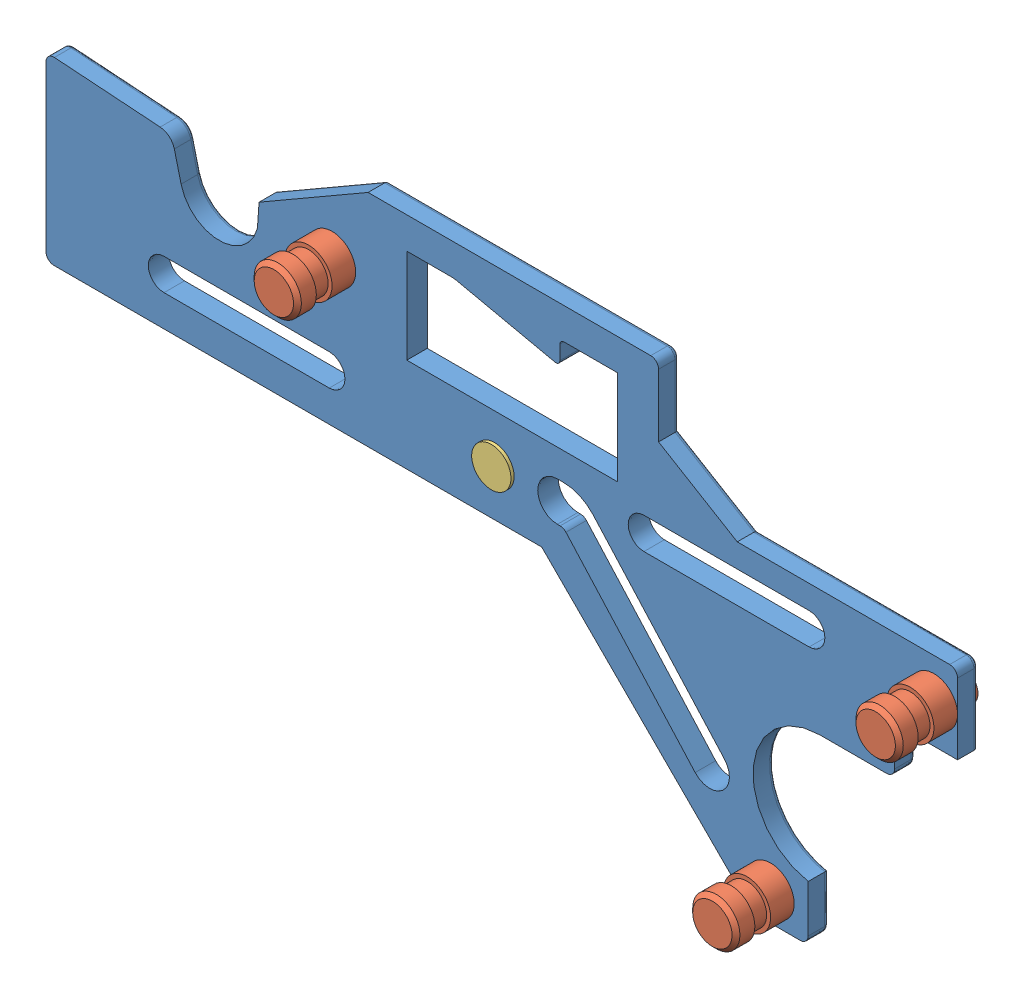
SolidWorks assembly plaque, configuration Défaut. Lengths in mm.
Overall size (115.86 55.31 11.5).
5 component instances, 3 part files, 8 mates.
Components (placement in the parent):
- Pièce8-1: Pièce8 [Défaut] at (-51.9489 -2.022 0) size (115.86 54.87 2.63)
- Pièce9-1: Pièce9 [Défaut] at (-15.5889 16.4069 10) x (0 0 -1) z (1 0 0) size (11 6 6)
- Pièce9-2: Pièce9 [Défaut] at (60.9111 5.978 10) x (0 0 -1) z (1 0 0) size (11 6 6)
- Pièce9-3: Pièce9 [Défaut] at (40.1491 -25.25 10) x (0 0 -1) z (0.486722 0.873557 0) size (11 6 6)
- Pièce10-1: Pièce10 [Défaut] at (5.0511 3.978 -1.5) x (0 0 1) z (-1 0 0) size (4.5 8 8)
Mates (geometry in assembly coordinates):
- Coaxiale1: concentric anti-aligned: cylinder of Pièce8-1 through (-15.5889 16.4069 0) axis (0 0 1) radius 2; cylinder of Pièce9-1 through (-15.5889 16.4069 -1) axis (0 0 -1) radius 2
- Coïncidente1: coincident anti-aligned: plane of Pièce8-1 through (-37.5769 17.9681 2.6) normal (0 0 1); plane of Pièce9-1 through (-15.5889 19.4069 2.6) normal (0 0 -1)
- Coïncidente2: coincident anti-aligned: cylinder of Pièce8-1 through (60.9111 5.978 0) axis (0 0 1) radius 2; circle of Pièce9-2
- Coïncidente3: coincident anti-aligned: plane of Pièce8-1 through (-37.5769 17.9681 2.6) normal (0 0 1); circle of Pièce9-2
- Coïncidente4: coincident anti-aligned: circle of Pièce8-1; cylinder of Pièce9-3 through (40.1491 -25.25 -1) axis (0 0 -1) radius 2
- Coïncidente5: coincident anti-aligned: plane of Pièce8-1 through (-37.5769 17.9681 2.6) normal (0 0 1); circle of Pièce9-3
- Coïncidente6: coincident aligned: circle of Pièce8-1; cylinder of Pièce10-1 through (5.0511 3.978 3) axis (0 0 1) radius 2.5
- Coïncidente7: coincident anti-aligned: plane of Pièce8-1 through (-37.5769 17.9681 0) normal (0 0 -1); circle of Pièce10-1
